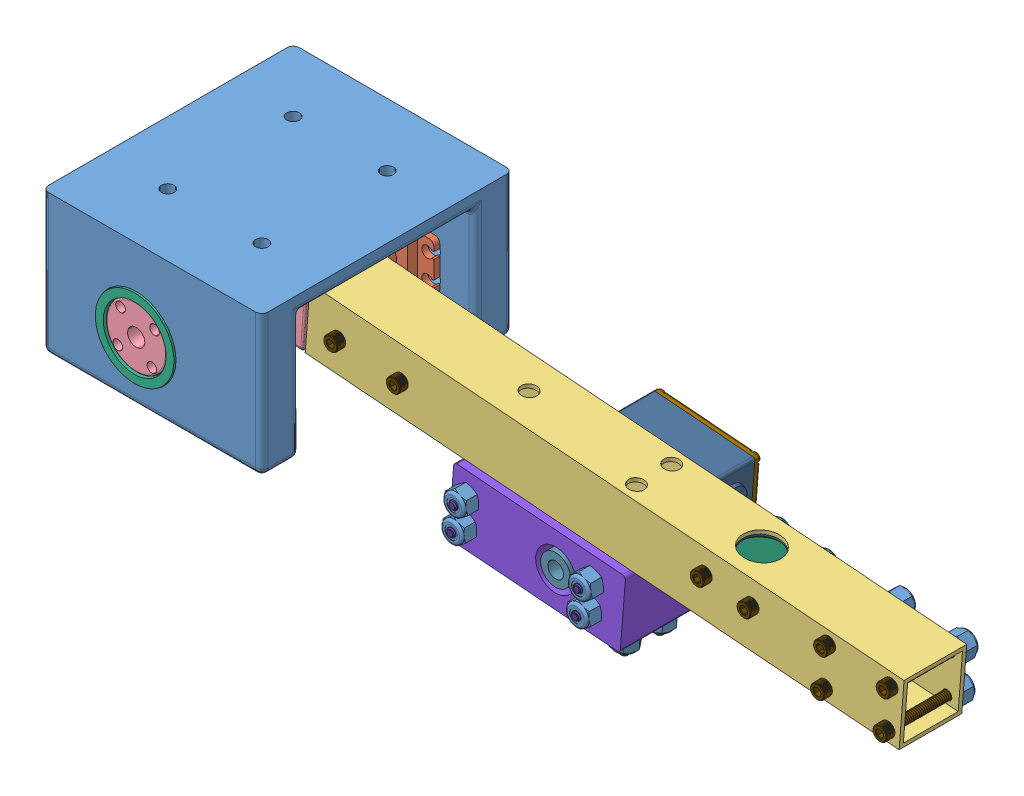
SolidWorks assembly MS-SA-0013d-03-Gripper Arm, configuration Default. Lengths in mm.
Overall size (306.45 94.86 113.6).
51 component instances, 19 part files, 106 mates.
Components (placement in the parent):
- MS-P-0057-03-Gripper Arm Mount-1: MS-P-0057-03-Gripper Arm Mount [Default] at (-52.2477 40.78 53.3156) x (0 0 1) z (0 1 0) size (101.6 88.9 57.15)
- MS-SA-0013b-03-Shoulder Servo Mount Assembly-1: MS-SA-0013b-03-Shoulder Servo Mount Assembly [Default] at (2.0387 62.0863 -50.1865) x (0 1 0) z (1 0 0) size (20 43.5 53.2)
  - MS-C-0032-Gripper Shoulder Servo-1: MS-C-0032-Gripper Shoulder Servo [Default] at (-48.0063 17.0406 -6.2663) x (0 0 -1) z (1 0 0) size (53.2 43.5 20)
- MS-P-0054-03-Box Tubing-1: MS-P-0054-03-Box Tubing [Default] at (11.7266 12.0316 -2.8819) x (0 0 -1) z (0.9969 -0.078677 0) size (25.4 25.4 241.3)
- MS-P-0058-03-Shoulder L Joint-1: MS-P-0058-03-Shoulder L Joint [Default] at (-14.2277 14.08 -2.1834) x (0 0 -1) z (0.9969 -0.078677 0) size (66.61 26.61 88.65)
- 525130.step-1: 525130.step [Default] at (-14.2277 14.08 -19.6459) x (0.078677 0.9969 0) z (0.9969 -0.078677 0) size (25.39 6.35 25.39)
- MS-C-0028-03-Servo Arm Bushing-1: MS-C-0028-03-Servo Arm Bushing [2934T25] at (-14.2277 14.08 34.9006) x (1 0 0) z (0 -1 0) size (38.1 19.05 38.1)
- 97171A170_ HEAT-SET INSERT FOR PLASTIC_V3-1: 97171A170_ HEAT-SET INSERT FOR PLASTIC_V3 [97171A170] at (19.7723 19.08 -40.131) x (-0.536856 0.843674 0) z (-0.843674 -0.536856 0) size (7.14 9.57 7.14)
- 97171A170_ HEAT-SET INSERT FOR PLASTIC_V3-2: 97171A170_ HEAT-SET INSERT FOR PLASTIC_V3 [97171A170] at (19.7723 9.08 -40.131) x (-0.383049 0.923728 0) z (-0.923728 -0.383049 0) size (7.14 9.57 7.14)
- 97171A170_ HEAT-SET INSERT FOR PLASTIC_V3-3: 97171A170_ HEAT-SET INSERT FOR PLASTIC_V3 [97171A170] at (-28.2277 19.08 -40.131) x (-0.940007 -0.341154 0) z (0.341154 -0.940007 0) size (7.14 9.57 7.14)
- 97171A170_ HEAT-SET INSERT FOR PLASTIC_V3-4: 97171A170_ HEAT-SET INSERT FOR PLASTIC_V3 [97171A170] at (-28.2277 9.08 -40.131) x (-0.231744 0.972777 0) z (-0.972777 -0.231744 0) size (7.14 9.57 7.14)
- MS-SA-0013a-03-Hand Servo Mount Assembly-1: MS-SA-0013a-03-Hand Servo Mount Assembly [Default] at (51.6986 -51.9207 16.8315) x (0 0 -1) z (0.9969 -0.078677 0) size (72.39 31.33 69.75)
  - MS-P-0055-03 Hand Servo Mount-1: MS-P-0055-03 Hand Servo Mount [Default] at (12.5808 33.9393 61.1705) size (41.76 27.94 69.75)
  - 11886-1: 11886 [Default] at (71.9223 31.717 49.4945) x (0 1 0) z (0 0 1) size (21 45.43 55.5)
    - 11886_bottom-1: 11886_bottom [Default] at (2.2223 -4.2785 0.9275) size (21 2.43 41.5)
    - 11886_middle-1: 11886_middle [Default] at (2.2223 -1.8785 0.9275) size (21 25.7 42.9)
    - 11886_upper-1: 11886_upper [Default] at (6.1473 23.8215 -5.3225) size (21 8.72 55.5)
    - 11886_top-1: 11886_top [Default] at (2.2223 32.5215 0.7275) size (20 8.6 36.5)
  - MS-C-0027-Servo Horn-1: MS-C-0027-Servo Horn [Default] at (34.0008 33.9393 61.172) x (0 0.962595 -0.270945) z (0 0.270945 0.962595) size (25.39 6.35 25.39)
  - MS-P-0060-03-Hand Servo Pulley-1: MS-P-0060-03-Hand Servo Pulley [Default] at (22.8883 33.9393 61.172) x (0 0.270945 0.962595) z (0 -0.962595 0.270945) size (25.4 23.81 25.4)
- MS-P-0047-Gripper Electromagnet Mount Inside Arm-1: MS-P-0047-Gripper Electromagnet Mount Inside Arm [Default] at (181.8873 -2.9901 -2.8819) x (0.9969 -0.078677 0) z (0 0 1) size (31.75 12.7 22.1)
- 92196A167_18-8 STAINLESS STEEL SOCKET HEAD SCREW-1: 92196A167_18-8 STAINLESS STEEL SOCKET HEAD SCREW [92196A167] at (134.4611 -47.0202 4.2619) x (0.178356 -0.014076 -0.983865) z (-0.078677 -0.9969 0) size (5.73 5.73 42.21)
- 92196A167_18-8 STAINLESS STEEL SOCKET HEAD SCREW-2: 92196A167_18-8 STAINLESS STEEL SOCKET HEAD SCREW [92196A167] at (134.4611 -47.0202 -10.0256) x (-0.009679 0.000764 -0.999953) z (-0.078677 -0.9969 0) size (5.73 5.73 42.21)
- 92196A167_18-8 STAINLESS STEEL SOCKET HEAD SCREW-3: 92196A167_18-8 STAINLESS STEEL SOCKET HEAD SCREW [92196A167] at (83.8186 -43.0235 -2.8819) x (-0.224346 0.017706 -0.974349) z (-0.078677 -0.9969 0) size (5.73 5.73 42.21)
- 92196A169_18-8 STAINLESS STEEL SOCKET HEAD SCREW-7: 92196A169_18-8 STAINLESS STEEL SOCKET HEAD SCREW [92196A169] at (79.7565 -15.0748 19.5306) x (-0.225494 0.974245 0) z (0 0 1) size (5.73 5.73 54.99)
- 92196A169_18-8 STAINLESS STEEL SOCKET HEAD SCREW-8: 92196A169_18-8 STAINLESS STEEL SOCKET HEAD SCREW [92196A169] at (78.9697 -25.0437 19.5306) x (0.191778 -0.981438 0) z (0 0 1) size (5.73 5.73 54.99)
- 92196A169_18-8 STAINLESS STEEL SOCKET HEAD SCREW-9: 92196A169_18-8 STAINLESS STEEL SOCKET HEAD SCREW [92196A169] at (130.2977 -19.0635 19.5306) x (0.056433 -0.998406 0) z (0 0 1) size (5.73 5.73 54.99)
- 92196A169_18-8 STAINLESS STEEL SOCKET HEAD SCREW-10: 92196A169_18-8 STAINLESS STEEL SOCKET HEAD SCREW [92196A169] at (129.511 -29.0325 19.5306) x (-0.049736 -0.998762 0) z (0 0 1) size (5.73 5.73 54.99)
- 92196A166_18-8 STAINLESS STEEL SOCKET HEAD SCREW-13: 92196A166_18-8 STAINLESS STEEL SOCKET HEAD SCREW [92196A166] at (172.7915 2.8236 -21.9319) x (0.59674 0.802434 0) z (0 0 -1) size (5.73 5.73 35.83)
- 92196A166_18-8 STAINLESS STEEL SOCKET HEAD SCREW-15: 92196A166_18-8 STAINLESS STEEL SOCKET HEAD SCREW [92196A166] at (191.7824 1.3248 -21.9319) x (0.615426 0.788195 0) z (0 0 -1) size (5.73 5.73 35.83)
- 90631A009_Low-Strength Steel Nylon-Insert Locknut-1: 90631A009_Low-Strength Steel Nylon-Insert Locknut [90631A009] at (84.493 -34.4775 -2.8819) x (-0.834574 0.065866 -0.546944) z (-0.545249 0.043032 0.837169) size (8.73 6.09 10.08)
- 90631A009_Low-Strength Steel Nylon-Insert Locknut-2: 90631A009_Low-Strength Steel Nylon-Insert Locknut [90631A009] at (135.1356 -38.4743 4.2619) x (-0.922375 0.072795 -0.379375) z (-0.378199 0.029848 0.925243) size (8.73 6.09 10.08)
- 90631A009_Low-Strength Steel Nylon-Insert Locknut-3: 90631A009_Low-Strength Steel Nylon-Insert Locknut [90631A009] at (135.1356 -38.4743 -10.0256) x (-0.982217 0.077518 -0.170998) z (-0.170468 0.013454 0.985271) size (8.73 6.09 10.08)
- 90631A009_Low-Strength Steel Nylon-Insert Locknut-5: 90631A009_Low-Strength Steel Nylon-Insert Locknut [90631A009] at (130.2977 -19.0635 12.9931) x (-0.987107 -0.16006 0) z (-0.16006 0.987107 0) size (8.73 6.09 10.08)
- 90631A009_Low-Strength Steel Nylon-Insert Locknut-7: 90631A009_Low-Strength Steel Nylon-Insert Locknut [90631A009] at (129.511 -29.0325 12.9931) x (-0.994509 -0.104651 0) z (-0.104651 0.994509 0) size (8.73 6.09 10.08)
- 90631A009_Low-Strength Steel Nylon-Insert Locknut-9: 90631A009_Low-Strength Steel Nylon-Insert Locknut [90631A009] at (79.7565 -15.0748 12.9931) x (-0.993677 -0.112278 0) z (-0.112278 0.993677 0) size (8.73 6.09 10.08)
- 90631A009_Low-Strength Steel Nylon-Insert Locknut-11: 90631A009_Low-Strength Steel Nylon-Insert Locknut [90631A009] at (78.9697 -25.0437 12.9931) x (-0.593284 0.804993 0) z (0.804993 0.593284 0) size (8.73 6.09 10.08)
- 90631A009_Low-Strength Steel Nylon-Insert Locknut-13: 90631A009_Low-Strength Steel Nylon-Insert Locknut [90631A009] at (191.7824 1.3248 -15.5819) x (0.013782 -0.999905 0) z (0.999905 0.013782 0) size (8.73 6.09 10.08)
- 90631A009_Low-Strength Steel Nylon-Insert Locknut-15: 90631A009_Low-Strength Steel Nylon-Insert Locknut [90631A009] at (172.7915 2.8236 -15.5819) x (0.187204 -0.982321 0) z (0.982321 0.187204 0) size (8.73 6.09 10.08)
- 92196A166_18-8 STAINLESS STEEL SOCKET HEAD SCREW-17: 92196A166_18-8 STAINLESS STEEL SOCKET HEAD SCREW [92196A166] at (222.7709 3.338 -21.9319) x (-0.902884 0.429884 0) z (0 0 -1) size (5.73 5.73 35.83)
- 92196A166_18-8 STAINLESS STEEL SOCKET HEAD SCREW-18: 92196A166_18-8 STAINLESS STEEL SOCKET HEAD SCREW [92196A166] at (248.0921 1.3396 -21.9319) x (0.224376 0.974503 0) z (0 0 -1) size (5.73 5.73 35.83)
- 92196A166_18-8 STAINLESS STEEL SOCKET HEAD SCREW-19: 92196A166_18-8 STAINLESS STEEL SOCKET HEAD SCREW [92196A166] at (221.5219 -12.4878 -21.9319) x (0.278925 0.960313 0) z (0 0 -1) size (5.73 5.73 35.83)
- 92196A166_18-8 STAINLESS STEEL SOCKET HEAD SCREW-20: 92196A166_18-8 STAINLESS STEEL SOCKET HEAD SCREW [92196A166] at (246.8431 -14.4862 -21.9319) x (0.226233 0.974073 0) z (0 0 -1) size (5.73 5.73 35.83)
- 92196A166_18-8 STAINLESS STEEL SOCKET HEAD SCREW-21: 92196A166_18-8 STAINLESS STEEL SOCKET HEAD SCREW [92196A166] at (24.3873 11.0324 -21.9319) x (0.216747 0.976228 0) z (0 0 -1) size (5.73 5.73 35.83)
- 92196A166_18-8 STAINLESS STEEL SOCKET HEAD SCREW-22: 92196A166_18-8 STAINLESS STEEL SOCKET HEAD SCREW [92196A166] at (49.7085 9.0341 -21.9319) x (0.256336 0.966588 0) z (0 0 -1) size (5.73 5.73 35.83)
- 90631A009_Low-Strength Steel Nylon-Insert Locknut-16: 90631A009_Low-Strength Steel Nylon-Insert Locknut [90631A009] at (222.7709 3.338 -15.5819) x (-0.973129 -0.230259 0) z (0.230259 -0.973129 0) size (8.73 6.09 10.08)
- 90631A009_Low-Strength Steel Nylon-Insert Locknut-17: 90631A009_Low-Strength Steel Nylon-Insert Locknut [90631A009] at (248.0921 1.3396 -15.5819) x (0.296175 -0.955134 0) z (0.955134 0.296175 0) size (8.73 6.09 10.08)
- 90631A009_Low-Strength Steel Nylon-Insert Locknut-18: 90631A009_Low-Strength Steel Nylon-Insert Locknut [90631A009] at (221.5219 -12.4878 -15.5819) x (0.383916 -0.923368 0) z (0.923368 0.383916 0) size (8.73 6.09 10.08)
- 90631A009_Low-Strength Steel Nylon-Insert Locknut-19: 90631A009_Low-Strength Steel Nylon-Insert Locknut [90631A009] at (246.8431 -14.4862 -15.5819) x (0.433613 -0.901099 0) z (0.901099 0.433613 0) size (8.73 6.09 10.08)
- 90631A009_Low-Strength Steel Nylon-Insert Locknut-20: 90631A009_Low-Strength Steel Nylon-Insert Locknut [90631A009] at (49.7085 9.0341 -15.5819) x (0.442359 -0.896838 0) z (0.896838 0.442359 0) size (8.73 6.09 10.08)
- 90631A009_Low-Strength Steel Nylon-Insert Locknut-21: 90631A009_Low-Strength Steel Nylon-Insert Locknut [90631A009] at (24.3873 11.0324 -15.5819) x (-0.623475 -0.781844 0) z (0.781844 -0.623475 0) size (8.73 6.09 10.08)
Mates (geometry in assembly coordinates):
- Distance1: distance = 6.35 mm anti-aligned: plane of MS-P-0047 - Gripper Arm Mount-1 through (95.6161 2.1794 54.1355) normal (0 0 -1); plane of GripperArm-1 through (52.9892 28.9852 43.023) normal (0 0 1)
- Concentric2: concentric aligned: cylinder of GripperArm-1 through (57.5161 21.2294 36.673) axis (0 0 1) radius 3.9688; cylinder of 6389K231_LIGHT DUTY DRY-RUNNING SLEEVE BEARING-1 through (19.4161 14.8794 63.9267) axis (0 0 1) radius 4.7625
- Coincident3: coincident anti-aligned: plane of MS-P-0057-03-Gripper Arm Mount-1 through (36.6523 47.13 53.3156) normal (0 0 1); plane of 6389K231_LIGHT DUTY DRY-RUNNING SLEEVE BEARING-2 through (19.4161 14.8794 69.3755) normal (0 0 -1)
- Concentric4: concentric anti-aligned: cylinder of 6389K231_LIGHT DUTY DRY-RUNNING SLEEVE BEARING-2 through (19.4161 14.8794 63.0255) axis (0 0 1) radius 3.175; cylinder of 90325A181_18-8 STAINLESS STEEL PRECISION SHOULDER SCREW-1 through (14.5574 87.2469 34.4811) axis (0 0 -1) radius 3.175
- Coincident4: coincident anti-aligned: plane of 6389K231_LIGHT DUTY DRY-RUNNING SLEEVE BEARING-2 through (19.4161 14.8794 70.963) normal (0 0 1); plane of 90325A181_18-8 STAINLESS STEEL PRECISION SHOULDER SCREW-1 through (14.5574 82.4844 59.8811) normal (0 0 -1)
- Concentric5: concentric anti-aligned: cylinder of 90325A181_18-8 STAINLESS STEEL PRECISION SHOULDER SCREW-1 through (14.5574 87.2469 34.4811) axis (0 0 -1) radius 1.6764; circle of 90631A011_LOW-STRENGTH STEEL NYLON-INSERT LOCKNUT-1
- Coincident5: coincident anti-aligned: plane of MS-P-0057-03-Gripper Arm Mount-1 through (36.6523 -10.02 38.0756) normal (0 0 -1); plane of 90631A011_LOW-STRENGTH STEEL NYLON-INSERT LOCKNUT-1 through (19.9239 88.4479 56.6755) normal (0 0 1)
- Concentric6: concentric aligned: cylinder of GripperArm-1 through (57.5161 21.2294 36.673) axis (0 0 1) radius 3.9688; cylinder of 98002A930_STEEL BINDING BARRELS AND SCREWS-1 through (19.4161 14.8794 61.9826) axis (0 0 1) radius 3.175
- Coincident6: coincident anti-aligned: plane of GripperArm-1 through (52.9892 28.9852 36.673) normal (0 0 -1); plane of 98002A930_STEEL BINDING BARRELS AND SCREWS-1 through (19.4161 14.8794 70.9629) normal (0 0 1)
- Coincident13: coincident anti-aligned: plane of MS-P-0057-03-Gripper Arm Mount-1 through (36.6523 -10.02 -33.0444) normal (0 0 1); plane of MS-A-0013 - Gripper Arm-1/MS-P-0048 - Servo Mount Piece-3 through (57.5161 40.2794 -42.3845) normal (0 0 -1)
- Concentric12: concentric anti-aligned: cylinder of MS-P-0057-03-Gripper Arm Mount-1 through (3.6323 28.08 53.3166) axis (0 0 -1) radius 2.54; cylinder of MS-A-0013 - Gripper Arm-1/MS-P-0048 - Servo Mount Piece-3 through (76.5661 40.2794 -42.3845) axis (0 0 1) radius 2.54
- Parallel1: parallel anti-aligned: cylinder of MS-P-0057-03-Gripper Arm Mount-1 through (-31.9277 -19.92 53.3166) axis (0 0 -1) radius 2.54; cylinder of MS-A-0013 - Gripper Arm-1/MS-P-0048 - Servo Mount Piece-4 through (38.6261 -10.4206 -42.3845) axis (0 0 1) radius 2.54
- Concentric15: concentric anti-aligned: cylinder of MS-P-0057-03-Gripper Arm Mount-1 through (-31.9277 28.08 53.3166) axis (0 0 -1) radius 2.54; cylinder of MS-A-0013 - Gripper Arm-1/MS-P-0048 - Servo Mount Piece-3 through (38.4661 40.2794 -42.3845) axis (0 0 1) radius 2.54
- Concentric16: concentric anti-aligned: circle of MS-P-0049- Gripper Arm Servo Horn Mount-1; circle of 525130.step-1
- Coincident15: coincident anti-aligned: plane of MS-P-0058-03-Shoulder L Joint-1 through (-14.2277 14.08 -13.2959) normal (0 0 -1); plane of 525130.step-1 through (-14.2277 14.08 -13.2959) normal (0 0 1)
- Concentric18: concentric anti-aligned: circle of MS-A-0013 - Gripper Arm-1/11886-2/11886_top-1; circle of 525130.step-1
- Coincident16: coincident anti-aligned: plane of MS-A-0013 - Gripper Arm-1/11886-2/11886_top-1 through (63.8475 25.5794 10.7295) normal (0 0 1); plane of 525130.step-1 through (-14.2277 14.08 -16.3439) normal (0 0 -1)
- Concentric20: concentric anti-aligned: circle of MS-A-0013 - Gripper Arm-1/MS-P-0048 - Servo Mount Piece-6; circle of MS-P-0047 - Gripper Arm Mount-1
- Coincident17: coincident anti-aligned: plane of MS-P-0057-03-Gripper Arm Mount-1 through (36.6523 -10.02 -33.0444) normal (0 0 1); plane of MS-A-0013 - Gripper Arm-1/MS-P-0048 - Servo Mount Piece-6 through (-14.1477 -19.92 -58.4444) normal (0 0 -1)
- Distance2: distance = 0.635 mm anti-aligned: plane of MS-P-0054-03-Box Tubing-1 through (11.7266 12.0316 -2.8819) normal (-0.9969 0.078677 0); plane of MS-P-0058-03-Shoulder L Joint-1 through (11.0936 12.0816 10.5166) normal (0.9969 -0.078677 0)
- Coincident20: coincident anti-aligned: plane of MS-P-0057-03-Gripper Arm Mount-1 through (36.6523 -10.02 38.0756) normal (0 0 -1); plane of MS-C-0028-03-Servo Arm Bushing-1 through (-14.2277 14.08 38.0756) normal (0 0 1)
- Concentric23: concentric aligned: cylinder of MS-P-0058-03-Shoulder L Joint-1 through (-14.2277 14.08 10.5166) axis (0 0 -1) radius 12.446; cylinder of MS-C-0028-03-Servo Arm Bushing-1 through (-14.2277 14.08 53.9506) axis (0 0 -1) radius 15.9004
- Concentric24: concentric aligned: circle of MS-A-0013 - Gripper Arm-1/MS-C-0029 - D956-WP Servo-1; circle of 525130.step-1
- Coincident21: coincident anti-aligned: plane of MS-A-0013b-03-Shoulder Servo Mount Assembly-1/MS-C-0032-Gripper Shoulder Servo-1 through (-14.2277 14.08 -19.6459) normal (0 0 1); plane of 525130.step-1 through (-14.2277 14.08 -19.6459) normal (0 0 -1)
- Width1: width anti-aligned: plane of MS-P-0058-03-Shoulder L Joint-1 through (60.9168 -2.2969 7.5321) normal (0 0 1); plane of MS-P-0058-03-Shoulder L Joint-1 through (-14.2277 14.08 -13.2959) normal (0 0 -1); plane of MS-P-0054-03-Box Tubing-1 through (253.2779 5.7076 -15.5819) normal (0 0 -1); plane of MS-P-0054-03-Box Tubing-1 through (253.2779 5.7076 9.8181) normal (0 0 1)
- Width2: width aligned: plane of MS-P-0058-03-Shoulder L Joint-1 through (60.9168 -2.2969 -13.2959) normal (-0.078677 -0.9969 0); plane of MS-P-0058-03-Shoulder L Joint-1 through (62.5555 18.4665 -13.2959) normal (0.078677 0.9969 0); plane of MS-P-0054-03-Box Tubing-1 through (251.2795 -19.6136 9.8181) normal (-0.078677 -0.9969 0); plane of MS-P-0054-03-Box Tubing-1 through (253.2779 5.7076 9.8181) normal (0.078677 0.9969 0)
- Concentric25: concentric aligned: circle of MS-P-0057-03-Gripper Arm Mount-1; circle of MS-C-0028-03-Servo Arm Bushing-1
- Coincident23: coincident aligned: plane of MS-P-0057-03-Gripper Arm Mount-1 through (36.6523 47.13 53.3156) normal (0 0 1); plane of MS-P-0058-03-Shoulder L Joint-1 through (-14.2277 14.08 53.3156) normal (0 0 1)
- Parallel2: parallel aligned: plane of MS-P-0057-03-Gripper Arm Mount-1 through (-52.2477 47.13 53.3156) normal (0 1 0); plane of MS-A-0013b-03-Shoulder Servo Mount Assembly-1/MS-C-0032-Gripper Shoulder Servo-1 through (-4.2277 24.08 -30.6459) normal (0 1 0)
- Concentric26: concentric aligned: circle of MS-P-0057-03-Gripper Arm Mount-1; circle of 97171A170_ HEAT-SET INSERT FOR PLASTIC_V3-1
- Coincident24: coincident anti-aligned: plane of MS-P-0057-03-Gripper Arm Mount-1 through (36.6523 47.13 -48.2844) normal (0 0 -1); plane of 97171A170_ HEAT-SET INSERT FOR PLASTIC_V3-1 through (18.4701 21.1265 -48.2844) normal (0 0 1)
- Concentric27: concentric aligned: circle of MS-P-0057-03-Gripper Arm Mount-1; circle of 97171A170_ HEAT-SET INSERT FOR PLASTIC_V3-2
- Coincident25: coincident anti-aligned: plane of MS-P-0057-03-Gripper Arm Mount-1 through (36.6523 47.13 -48.2844) normal (0 0 -1); plane of 97171A170_ HEAT-SET INSERT FOR PLASTIC_V3-2 through (18.8432 11.3207 -48.2844) normal (0 0 1)
- Concentric28: concentric anti-aligned: circle of MS-A-0013b-03-Shoulder Servo Mount Assembly-1/MS-C-0032-Gripper Shoulder Servo-1; circle of 97171A170_ HEAT-SET INSERT FOR PLASTIC_V3-3
- Coincident27: coincident anti-aligned: plane of MS-P-0057-03-Gripper Arm Mount-1 through (36.6523 47.13 -48.2844) normal (0 0 -1); plane of 97171A170_ HEAT-SET INSERT FOR PLASTIC_V3-3 through (-30.5078 18.2524 -48.2844) normal (0 0 1)
- Concentric29: concentric aligned: circle of MS-A-0013b-03-Shoulder Servo Mount Assembly-1/MS-C-0032-Gripper Shoulder Servo-1; circle of 97171A170_ HEAT-SET INSERT FOR PLASTIC_V3-4
- Coincident28: coincident anti-aligned: plane of MS-P-0057-03-Gripper Arm Mount-1 through (36.6523 47.13 -48.2844) normal (0 0 -1); plane of 97171A170_ HEAT-SET INSERT FOR PLASTIC_V3-4 through (-28.7898 11.4396 -48.2844) normal (0 0 1)
- Coincident29: coincident anti-aligned: plane of MS-P-0057-03-Gripper Arm Mount-1 through (36.6523 -10.02 -33.0444) normal (0 0 1); plane of 97171A170_ HEAT-SET INSERT FOR PLASTIC_V3-5 through (25.2931 19.7789 -33.0444) normal (0 0 -1)
- Coincident30: coincident anti-aligned: plane of MS-P-0057-03-Gripper Arm Mount-1 through (36.6523 -10.02 -33.0444) normal (0 0 1); plane of 97171A170_ HEAT-SET INSERT FOR PLASTIC_V3-6 through (25.6708 9.88 -33.0444) normal (0 0 -1)
- Concentric30: concentric aligned: circle of MS-P-0054-03-Box Tubing-1; circle of MS-SA-0013a-03-Hand Servo Mount Assembly-1/MS-P-0055-03 Hand Servo Mount-1
- Concentric31: concentric aligned: circle of MS-P-0054-03-Box Tubing-1; circle of MS-SA-0013a-03-Hand Servo Mount Assembly-1/MS-P-0055-03 Hand Servo Mount-1
- Coincident31: coincident anti-aligned: plane of MS-P-0054-03-Box Tubing-1 through (251.2795 -19.6136 9.8181) normal (-0.078677 -0.9969 0); plane of MS-SA-0013a-03-Hand Servo Mount Assembly-1/MS-P-0055-03 Hand Servo Mount-1 through (116.4488 -8.9727 88.1295) normal (0.078677 0.9969 0)
- Width3: width anti-aligned: plane of MS-P-0054-03-Box Tubing-1 through (253.153 4.125 8.2306) normal (0 0 -1); plane of MS-P-0054-03-Box Tubing-1 through (253.153 4.125 -13.9944) normal (0 0 1); plane of MS-P-0047-Gripper Electromagnet Mount Inside Arm-1 through (167.0607 10.9195 8.1671) normal (0 0 1); plane of MS-P-0047-Gripper Electromagnet Mount Inside Arm-1 through (167.0607 10.9195 -13.9309) normal (0 0 -1)
- Coincident32: coincident anti-aligned: plane of MS-P-0054-03-Box Tubing-1 through (253.153 4.125 8.2306) normal (-0.078677 -0.9969 0); plane of MS-P-0047-Gripper Electromagnet Mount Inside Arm-1 through (182.8864 9.6706 -2.8819) normal (0.078677 0.9969 0)
- Concentric32: concentric aligned: circle of MS-P-0054-03-Box Tubing-1; circle of MS-P-0047-Gripper Electromagnet Mount Inside Arm-1
- LimitAngle1: limit planar angle = 0.078758 rad aligned: plane of MS-P-0054-03-Box Tubing-1 through (253.2779 5.7076 9.8181) normal (0.078677 0.9969 0); plane of MS-P-0057-03-Gripper Arm Mount-1 through (-52.2477 47.13 53.3156) normal (0 1 0)
- Concentric33: concentric aligned: circle of MS-SA-0013a-03-Hand Servo Mount Assembly-1/MS-P-0055-03 Hand Servo Mount-1; circle of 92196A169_18-8 STAINLESS STEEL SOCKET HEAD SCREW-1
- Coincident36: coincident anti-aligned: plane of MS-P-0054-03-Box Tubing-1 through (251.4044 -18.0311 8.2306) normal (0.078677 0.9969 0); plane of 92196A167_18-8 STAINLESS STEEL SOCKET HEAD SCREW-1 through (137.4587 -9.0383 4.2619) normal (-0.078677 -0.9969 0)
- Concentric34: concentric aligned: circle of MS-SA-0013a-03-Hand Servo Mount Assembly-1/MS-P-0055-03 Hand Servo Mount-1; circle of 92196A169_18-8 STAINLESS STEEL SOCKET HEAD SCREW-2
- Coincident37: coincident anti-aligned: plane of MS-P-0054-03-Box Tubing-1 through (251.4044 -18.0311 8.2306) normal (0.078677 0.9969 0); plane of 92196A167_18-8 STAINLESS STEEL SOCKET HEAD SCREW-2 through (137.4587 -9.0383 -10.0256) normal (-0.078677 -0.9969 0)
- Coincident38: coincident anti-aligned: plane of MS-P-0054-03-Box Tubing-1 through (251.4044 -18.0311 8.2306) normal (0.078677 0.9969 0); plane of 92196A167_18-8 STAINLESS STEEL SOCKET HEAD SCREW-3 through (86.8161 -5.0416 -2.8819) normal (-0.078677 -0.9969 0)
- Concentric35: concentric aligned: circle of MS-SA-0013a-03-Hand Servo Mount Assembly-1/MS-P-0055-03 Hand Servo Mount-1; circle of 92196A169_18-8 STAINLESS STEEL SOCKET HEAD SCREW-3
- Concentric37: concentric aligned: circle of MS-SA-0013a-03-Hand Servo Mount Assembly-1/MS-P-0055-03 Hand Servo Mount-1; circle of 92196A169_18-8 STAINLESS STEEL SOCKET HEAD SCREW-7
- Concentric38: concentric aligned: circle of MS-SA-0013a-03-Hand Servo Mount Assembly-1/MS-P-0055-03 Hand Servo Mount-1; circle of 92196A169_18-8 STAINLESS STEEL SOCKET HEAD SCREW-8
- Concentric39: concentric aligned: circle of MS-SA-0013a-03-Hand Servo Mount Assembly-1/MS-P-0055-03 Hand Servo Mount-1; circle of 92196A169_18-8 STAINLESS STEEL SOCKET HEAD SCREW-9
- Concentric40: concentric aligned: circle of MS-SA-0013a-03-Hand Servo Mount Assembly-1/MS-P-0055-03 Hand Servo Mount-1; circle of 92196A169_18-8 STAINLESS STEEL SOCKET HEAD SCREW-10
- Concentric41: concentric aligned: circle of MS-P-0047-Gripper Electromagnet Mount Inside Arm-1; circle of 92196A169_18-8 STAINLESS STEEL SOCKET HEAD SCREW-13
- Concentric42: concentric aligned: circle of MS-P-0047-Gripper Electromagnet Mount Inside Arm-1; circle of 92196A169_18-8 STAINLESS STEEL SOCKET HEAD SCREW-15
- Concentric43: concentric anti-aligned: circle of 90631A009_LOW-STRENGTH STEEL NYLON-INSERT LOCKNUT-1; circle of MS-SA-0013a-03-Hand Servo Mount Assembly-1/MS-P-0055-03 Hand Servo Mount-1
- Coincident52: coincident anti-aligned: plane of MS-SA-0013a-03-Hand Servo Mount Assembly-1/MS-P-0055-03 Hand Servo Mount-1 through (114.2506 -36.826 88.1295) normal (-0.078677 -0.9969 0); plane of 90631A009_LOW-STRENGTH STEEL NYLON-INSERT LOCKNUT-1 through (92.2594 -35.0905 -6.8244) normal (0.078677 0.9969 0)
- Concentric44: concentric anti-aligned: circle of MS-SA-0013a-03-Hand Servo Mount Assembly-1/MS-P-0055-03 Hand Servo Mount-1; circle of 90631A009_LOW-STRENGTH STEEL NYLON-INSERT LOCKNUT-2
- Coincident53: coincident anti-aligned: plane of MS-SA-0013a-03-Hand Servo Mount Assembly-1/MS-P-0055-03 Hand Servo Mount-1 through (114.2506 -36.826 88.1295) normal (-0.078677 -0.9969 0); plane of 90631A009_LOW-STRENGTH STEEL NYLON-INSERT LOCKNUT-2 through (142.022 -39.0178 -1.0781) normal (0.078677 0.9969 0)
- Coincident54: coincident anti-aligned: plane of MS-SA-0013a-03-Hand Servo Mount Assembly-1/MS-P-0055-03 Hand Servo Mount-1 through (114.2506 -36.826 88.1295) normal (-0.078677 -0.9969 0); plane of 90631A009_LOW-STRENGTH STEEL NYLON-INSERT LOCKNUT-3 through (140.7125 -38.9145 -16.7292) normal (0.078677 0.9969 0)
- Concentric45: concentric anti-aligned: circle of MS-SA-0013a-03-Hand Servo Mount Assembly-1/MS-P-0055-03 Hand Servo Mount-1; circle of 90631A009_LOW-STRENGTH STEEL NYLON-INSERT LOCKNUT-3
- Coincident57: coincident anti-aligned: plane of MS-SA-0013a-03-Hand Servo Mount Assembly-1/11886-1/11886_upper-1 through (83.1227 -30.8886 -31.2694) normal (0 0 -1); plane of 92196A169_18-8 STAINLESS STEEL SOCKET HEAD SCREW-7 through (79.7565 -15.0748 -31.2694) normal (0 0 1)
- Coincident58: coincident anti-aligned: plane of MS-SA-0013a-03-Hand Servo Mount Assembly-1/11886-1/11886_upper-1 through (83.1227 -30.8886 -31.2694) normal (0 0 -1); plane of 92196A169_18-8 STAINLESS STEEL SOCKET HEAD SCREW-8 through (78.9697 -25.0437 -31.2694) normal (0 0 1)
- Coincident59: coincident anti-aligned: plane of MS-SA-0013a-03-Hand Servo Mount Assembly-1/11886-1/11886_upper-1 through (83.1227 -30.8886 -31.2694) normal (0 0 -1); plane of 92196A169_18-8 STAINLESS STEEL SOCKET HEAD SCREW-9 through (130.2977 -19.0635 -31.2694) normal (0 0 1)
- Coincident60: coincident anti-aligned: plane of MS-SA-0013a-03-Hand Servo Mount Assembly-1/11886-1/11886_upper-1 through (83.1227 -30.8886 -31.2694) normal (0 0 -1); plane of 92196A169_18-8 STAINLESS STEEL SOCKET HEAD SCREW-10 through (129.511 -29.0325 -31.2694) normal (0 0 1)
- Concentric47: concentric anti-aligned: circle of MS-SA-0013a-03-Hand Servo Mount Assembly-1/MS-P-0055-03 Hand Servo Mount-1; circle of 90631A009_LOW-STRENGTH STEEL NYLON-INSERT LOCKNUT-5
- Coincident61: coincident anti-aligned: plane of MS-SA-0013a-03-Hand Servo Mount Assembly-1/MS-P-0055-03 Hand Servo Mount-1 through (115.3512 -22.8995 12.9931) normal (0 0 1); plane of 90631A009_LOW-STRENGTH STEEL NYLON-INSERT LOCKNUT-5 through (135.8174 -25.8288 12.9931) normal (0 0 -1)
- Concentric50: concentric anti-aligned: circle of MS-SA-0013a-03-Hand Servo Mount Assembly-1/MS-P-0055-03 Hand Servo Mount-1; circle of 90631A009_LOW-STRENGTH STEEL NYLON-INSERT LOCKNUT-7
- Coincident63: coincident anti-aligned: plane of MS-SA-0013a-03-Hand Servo Mount Assembly-1/MS-P-0055-03 Hand Servo Mount-1 through (115.3512 -22.8995 12.9931) normal (0 0 1); plane of 90631A009_LOW-STRENGTH STEEL NYLON-INSERT LOCKNUT-7 through (134.6439 -36.0956 12.9931) normal (0 0 -1)
- Concentric51: concentric anti-aligned: circle of MS-SA-0013a-03-Hand Servo Mount Assembly-1/MS-P-0055-03 Hand Servo Mount-1; circle of 90631A009_LOW-STRENGTH STEEL NYLON-INSERT LOCKNUT-9
- Coincident64: coincident anti-aligned: plane of MS-SA-0013a-03-Hand Servo Mount Assembly-1/MS-P-0055-03 Hand Servo Mount-1 through (115.3512 -22.8995 12.9931) normal (0 0 1); plane of 90631A009_LOW-STRENGTH STEEL NYLON-INSERT LOCKNUT-9 through (84.9435 -22.0983 12.9931) normal (0 0 -1)
- Concentric52: concentric anti-aligned: circle of MS-SA-0013a-03-Hand Servo Mount Assembly-1/MS-P-0055-03 Hand Servo Mount-1; circle of 90631A009_LOW-STRENGTH STEEL NYLON-INSERT LOCKNUT-11
- Coincident65: coincident anti-aligned: plane of MS-SA-0013a-03-Hand Servo Mount Assembly-1/MS-P-0055-03 Hand Servo Mount-1 through (115.3512 -22.8995 12.9931) normal (0 0 1); plane of 90631A009_LOW-STRENGTH STEEL NYLON-INSERT LOCKNUT-11 through (75.4728 -33.0441 12.9931) normal (0 0 -1)
- Concentric53: concentric anti-aligned: circle of MS-P-0054-03-Box Tubing-1; circle of 90631A009_LOW-STRENGTH STEEL NYLON-INSERT LOCKNUT-13
- Coincident66: coincident anti-aligned: plane of MS-P-0054-03-Box Tubing-1 through (253.2779 5.7076 -15.5819) normal (0 0 -1); plane of 90631A009_LOW-STRENGTH STEEL NYLON-INSERT LOCKNUT-13 through (184.1615 5.5858 -15.5819) normal (0 0 1)
- Concentric54: concentric anti-aligned: circle of MS-P-0054-03-Box Tubing-1; circle of 90631A009_LOW-STRENGTH STEEL NYLON-INSERT LOCKNUT-15
- Coincident67: coincident anti-aligned: plane of MS-P-0054-03-Box Tubing-1 through (253.2779 5.7076 -15.5819) normal (0 0 -1); plane of 90631A009_LOW-STRENGTH STEEL NYLON-INSERT LOCKNUT-15 through (164.5464 5.6965 -15.5819) normal (0 0 1)
- Coincident68: coincident anti-aligned: plane of MS-P-0054-03-Box Tubing-1 through (253.2779 5.7076 9.8181) normal (0 0 1); plane of 92196A166_18-8 STAINLESS STEEL SOCKET HEAD SCREW-13 through (172.7915 2.8236 9.8181) normal (0 0 -1)
- Coincident69: coincident anti-aligned: plane of MS-P-0054-03-Box Tubing-1 through (253.2779 5.7076 9.8181) normal (0 0 1); plane of 92196A166_18-8 STAINLESS STEEL SOCKET HEAD SCREW-15 through (191.7824 1.3248 9.8181) normal (0 0 -1)
- Concentric55: concentric anti-aligned: circle of MS-P-0054-03-Box Tubing-1; circle of 92196A166_18-8 STAINLESS STEEL SOCKET HEAD SCREW-17
- Coincident70: coincident anti-aligned: plane of MS-P-0054-03-Box Tubing-1 through (253.2779 5.7076 9.8181) normal (0 0 1); plane of 92196A166_18-8 STAINLESS STEEL SOCKET HEAD SCREW-17 through (222.7709 3.338 9.8181) normal (0 0 -1)
- Coincident71: coincident: plane of MS-P-0054-03-Box Tubing-1 through (241.8883 -63.5982 9.8181) normal (0 0 1); plane of 92196A166_18-8 STAINLESS STEEL SOCKET HEAD SCREW-18
- Concentric56: concentric anti-aligned: circle of MS-P-0054-03-Box Tubing-1; circle of 92196A166_18-8 STAINLESS STEEL SOCKET HEAD SCREW-18
- Coincident72: coincident: plane of MS-P-0054-03-Box Tubing-1 through (241.8883 -63.5982 9.8181) normal (0 0 1); plane of 92196A166_18-8 STAINLESS STEEL SOCKET HEAD SCREW-19
- Concentric57: concentric anti-aligned: circle of MS-P-0054-03-Box Tubing-1; circle of 92196A166_18-8 STAINLESS STEEL SOCKET HEAD SCREW-19
- Coincident73: coincident anti-aligned: plane of MS-P-0054-03-Box Tubing-1 through (253.2779 5.7076 9.8181) normal (0 0 1); plane of 92196A166_18-8 STAINLESS STEEL SOCKET HEAD SCREW-20 through (246.8431 -14.4862 9.8181) normal (0 0 -1)
- Concentric58: concentric anti-aligned: circle of MS-P-0054-03-Box Tubing-1; circle of 92196A166_18-8 STAINLESS STEEL SOCKET HEAD SCREW-20
- Coincident74: coincident anti-aligned: plane of MS-P-0054-03-Box Tubing-1 through (253.2779 5.7076 9.8181) normal (0 0 1); plane of 92196A166_18-8 STAINLESS STEEL SOCKET HEAD SCREW-21 through (24.3873 11.0324 9.8181) normal (0 0 -1)
- Concentric59: concentric aligned: circle of MS-P-0054-03-Box Tubing-1; circle of 92196A166_18-8 STAINLESS STEEL SOCKET HEAD SCREW-21
- Coincident75: coincident anti-aligned: plane of MS-P-0054-03-Box Tubing-1 through (253.2779 5.7076 9.8181) normal (0 0 1); plane of 92196A166_18-8 STAINLESS STEEL SOCKET HEAD SCREW-22 through (49.7085 9.0341 9.8181) normal (0 0 -1)
- Concentric60: concentric aligned: circle of MS-P-0054-03-Box Tubing-1; circle of 92196A166_18-8 STAINLESS STEEL SOCKET HEAD SCREW-22
- Concentric61: concentric aligned: circle of MS-P-0054-03-Box Tubing-1; circle of 90631A009_LOW-STRENGTH STEEL NYLON-INSERT LOCKNUT-16
- Coincident77: coincident anti-aligned: plane of MS-P-0054-03-Box Tubing-1 through (253.2779 5.7076 -15.5819) normal (0 0 -1); plane of 90631A009_LOW-STRENGTH STEEL NYLON-INSERT LOCKNUT-16 through (225.2781 11.7015 -15.5819) normal (0 0 1)
- Coincident78: coincident anti-aligned: plane of MS-P-0054-03-Box Tubing-1 through (253.2779 5.7076 -15.5819) normal (0 0 -1); plane of 90631A009_LOW-STRENGTH STEEL NYLON-INSERT LOCKNUT-17 through (239.5769 3.2698 -15.5819) normal (0 0 1)
- Concentric62: concentric aligned: circle of MS-P-0054-03-Box Tubing-1; circle of 90631A009_LOW-STRENGTH STEEL NYLON-INSERT LOCKNUT-17
- Coincident79: coincident anti-aligned: plane of MS-P-0054-03-Box Tubing-1 through (253.2779 5.7076 -15.5819) normal (0 0 -1); plane of 90631A009_LOW-STRENGTH STEEL NYLON-INSERT LOCKNUT-18 through (212.8638 -11.3597 -15.5819) normal (0 0 1)
- Concentric63: concentric aligned: circle of MS-P-0054-03-Box Tubing-1; circle of 90631A009_LOW-STRENGTH STEEL NYLON-INSERT LOCKNUT-18
- Coincident80: coincident anti-aligned: plane of MS-P-0054-03-Box Tubing-1 through (253.2779 5.7076 -15.5819) normal (0 0 -1); plane of 90631A009_LOW-STRENGTH STEEL NYLON-INSERT LOCKNUT-19 through (238.1365 -13.8311 -15.5819) normal (0 0 1)
- Concentric64: concentric aligned: circle of MS-P-0054-03-Box Tubing-1; circle of 90631A009_LOW-STRENGTH STEEL NYLON-INSERT LOCKNUT-19
- Coincident81: coincident anti-aligned: plane of MS-P-0054-03-Box Tubing-1 through (253.2779 5.7076 -15.5819) normal (0 0 -1); plane of 90631A009_LOW-STRENGTH STEEL NYLON-INSERT LOCKNUT-20 through (40.9959 9.6044 -15.5819) normal (0 0 1)
- Concentric65: concentric aligned: circle of MS-P-0054-03-Box Tubing-1; circle of 90631A009_LOW-STRENGTH STEEL NYLON-INSERT LOCKNUT-20
- Coincident82: coincident anti-aligned: plane of MS-P-0054-03-Box Tubing-1 through (253.2779 5.7076 -15.5819) normal (0 0 -1); plane of 90631A009_LOW-STRENGTH STEEL NYLON-INSERT LOCKNUT-21 through (21.1972 19.1601 -15.5819) normal (0 0 1)
- Concentric66: concentric anti-aligned: circle of MS-P-0054-03-Box Tubing-1; circle of 90631A009_LOW-STRENGTH STEEL NYLON-INSERT LOCKNUT-21
